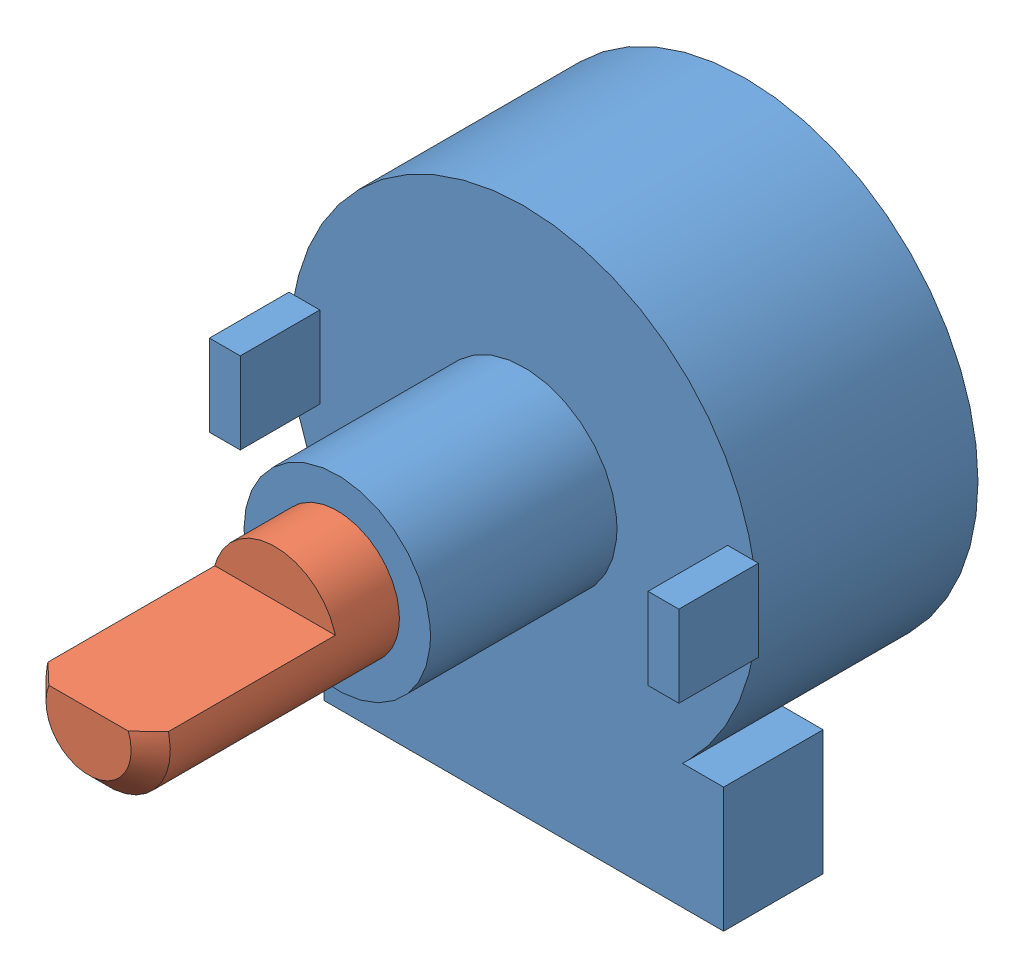
SolidWorks assembly pot, configuration Default. Lengths in mm.
Overall size (23.98 26.99 33.53).
2 component instances, 2 part files, 3 mates.
Components (placement in the parent):
- potBody-1: potBody [Default] at (2.1373 17.8173 24.3383) size (23.98 26.99 20.83)
- potShaft-1: potShaft [Default] at (2.1373 17.8173 24.3383) size (6.35 6.35 22.23)
Mates (geometry in assembly coordinates):
- Coincident1: coincident anti-aligned: plane of potBody-1 through (2.1373 17.8173 24.3383) normal (0 0 1); plane of potShaft-1 through (2.1373 17.8173 24.3383) normal (0 0 -1)
- LimitAngle1: limit planar angle = 3.141593 rad aligned: plane of potBody-1 through (-8.0735 2.7297 19.2583) normal (0 -1 0); plane of potShaft-1 through (-0.9385 18.6047 76.5268) normal (0 1 0)
- Concentric1: concentric anti-aligned: cylinder of potBody-1 through (2.1373 17.8173 24.3383) axis (0 0 1) radius 3.175; cylinder of potShaft-1 through (2.1373 17.8173 46.5633) axis (0 0 -1) radius 3.175
